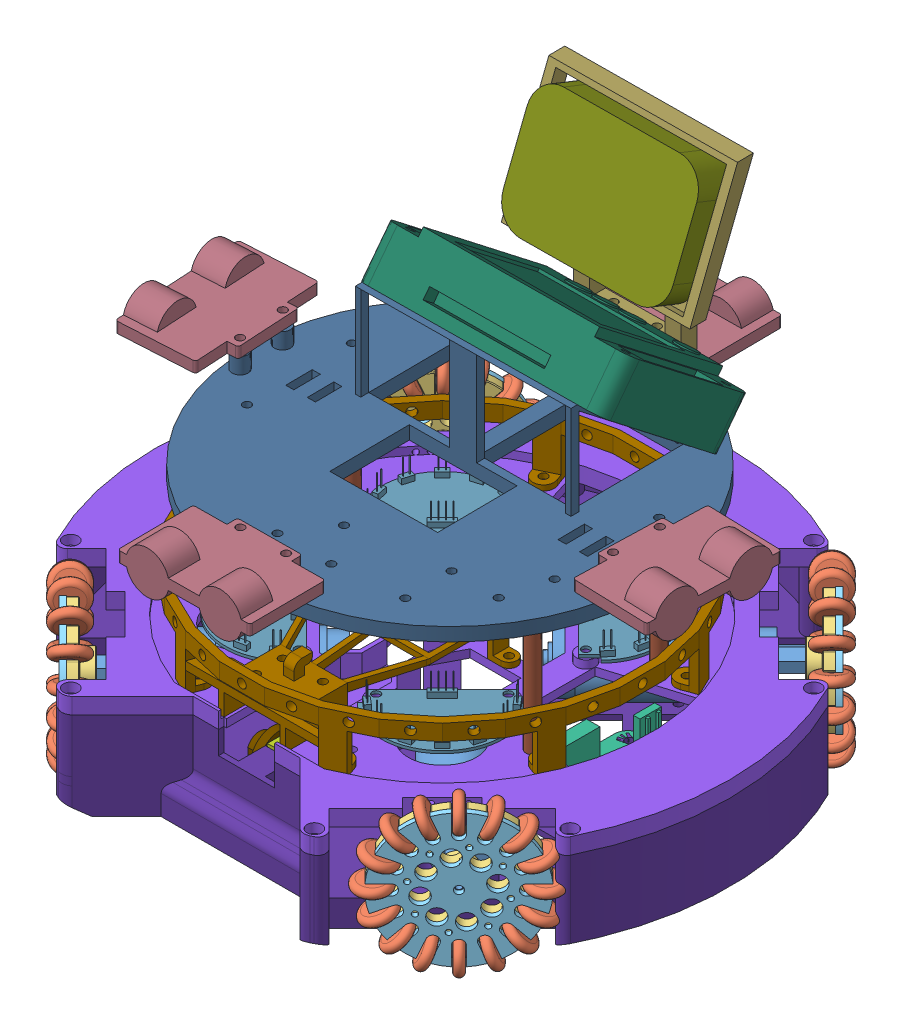
SolidWorks assembly 0623, configuration 默认. Lengths in mm.
Overall size (215 174.45 207.54).
171 component instances, 18 part files, 36 mates.
Components (placement in the parent):
- 马达25-1: 马达25 [預設] at (54.8373 -31.5326 209.9849) x (-0.000306 -1 -0.000306) z (-0.707107 0 0.707107) size (61.22 59.79 89.47)
  - 輕量空心杯電機BY亨哥-1: 輕量空心杯電機BY亨哥 [預設] at (4.2662 -2.1089 38.7) size (23 23 77.4)
  - 全向輪-1: 全向輪 [預設] at (-15.6348 -2.7534 102.1854) x (0.994045 0 -0.108967) z (0.108967 0 0.994045) size (59.43 59.79 19.63)
    - 小輪-3: 小輪 [預設] at (-13.3411 -5.1734 12.5) size (12.5 3.5 12.5)
    - 全向輪鋁-3: 全向輪鋁 [預設] at (18.6476 0.6445 12.5211) x (0.994045 0 0.108967) z (-0.108967 0 0.994045) size (49.74 49.74 8)
    - 軸-3: 軸 [預設] at (-4.4878 -6.2404 12.5) x (0 -1 0) z (-0.050863 0 0.998706) size (8.5 2 2)
    - 壓片-3: 壓片 [預設] at (18.2663 0.6445 16.0003) x (0.994045 0 0.108967) z (-0.108967 0 0.994045) size (49.84 49.84 2)
    - 軸-35: 軸 [預設] at (-0.1284 -14.518 12.9779) x (0.380405 -0.92388 0.0417) z (-0.055272 0.022297 0.998222) size (8.5 2 2)
    - 軸-36: 軸 [預設] at (7.048 -20.4873 13.7646) x (0.702896 -0.707107 0.077052) z (-0.067827 0.0412 0.996846) size (8.5 2 2)
    - 軸-37: 軸 [預設] at (15.9489 -23.2394 14.7403) x (0.918378 -0.382683 0.100673) z (-0.086618 0.053831 0.994786) size (8.5 2 2)
    - 軸-38: 軸 [預設] at (25.2192 -22.3555 15.7565) x (0.994045 0 0.108967) z (-0.108782 0.058266 0.992357) size (8.5 2 2)
    - 軸-39: 軸 [預設] at (33.4475 -17.9699 16.6585) x (0.918378 0.382683 0.100673) z (-0.130947 0.053831 0.989927) size (8.5 2 2)
    - 軸-40: 軸 [預設] at (39.3812 -10.7505 17.3089) x (0.702896 0.707107 0.077052) z (-0.149737 0.0412 0.987867) size (8.5 2 2)
    - 軸-41: 軸 [預設] at (42.117 -1.7963 17.6088) x (0.380405 0.92388 0.0417) z (-0.162293 0.022297 0.986491) size (8.5 2 2)
    - 軸-42: 軸 [預設] at (41.2383 7.5295 17.5125) x (0 1 0) z (-0.166701 0 0.986007) size (8.5 2 2)
    - 軸-43: 軸 [預設] at (36.8789 15.8071 17.0346) x (-0.380405 0.92388 -0.0417) z (-0.162293 -0.022297 0.986491) size (8.5 2 2)
    - 軸-44: 軸 [預設] at (29.7024 21.7764 16.2479) x (-0.702896 0.707107 -0.077052) z (-0.149737 -0.0412 0.987867) size (8.5 2 2)
    - 軸-45: 軸 [預設] at (20.8015 24.5285 15.2722) x (-0.918378 0.382683 -0.100673) z (-0.130947 -0.053831 0.989927) size (8.5 2 2)
    - 軸-46: 軸 [預設] at (11.5313 23.6445 14.256) x (-0.994045 0 -0.108967) z (-0.108782 -0.058266 0.992357) size (8.5 2 2)
    - 軸-47: 軸 [預設] at (3.3029 19.259 13.354) x (-0.918378 -0.382683 -0.100673) z (-0.086618 -0.053831 0.994786) size (8.5 2 2)
    - 軸-48: 軸 [預設] at (-2.6308 12.0396 12.7036) x (-0.702896 -0.707107 -0.077052) z (-0.067827 -0.0412 0.996846) size (8.5 2 2)
    - 軸-49: 軸 [預設] at (-5.3665 3.0854 12.4037) x (-0.380405 -0.92388 -0.0417) z (-0.055272 -0.022297 0.998222) size (8.5 2 2)
    - 小輪-4: 小輪 [預設] at (-8.7217 -16.9001 13.0064) x (0.924783 0.380405 -0.008245) z (-0.008245 0.0417 0.999096) size (12.5 3.5 12.5)
    - 小輪-5: 小輪 [預設] at (0.007 -25.9558 13.9632) x (0.710585 0.702896 -0.031726) z (-0.031726 0.077052 0.996522) size (12.5 3.5 12.5)
    - 小輪-6: 小輪 [預設] at (11.516 -30.9618 15.2248) x (0.390013 0.918378 -0.066867) z (-0.066867 0.100673 0.99267) size (12.5 3.5 12.5)
    - 小輪-7: 小輪 [預設] at (24.0533 -31.1561 16.5992) x (0.011874 0.994045 -0.108319) z (-0.108319 0.108967 0.988126) size (12.5 3.5 12.5)
    - 小輪-8: 小輪 [預設] at (35.7102 -26.509 17.877) x (-0.366266 0.918378 -0.14977) z (-0.14977 0.100673 0.983582) size (12.5 3.5 12.5)
    - 小輪-9: 小輪 [預設] at (44.712 -17.728 18.8638) x (-0.686837 0.702896 -0.184911) z (-0.184911 0.077052 0.97973) size (12.5 3.5 12.5)
    - 小輪-10: 小輪 [預設] at (49.6882 -6.15 19.4093) x (-0.901036 0.380405 -0.208392) z (-0.208392 0.0417 0.977156) size (12.5 3.5 12.5)
    - 小輪-11: 小輪 [預設] at (49.8813 6.4624 19.4305) x (-0.976252 0 -0.216637) z (-0.216637 0 0.976252) size (12.5 3.5 12.5)
    - 小輪-12: 小輪 [預設] at (45.2619 18.1891 18.9241) x (-0.901036 -0.380405 -0.208392) z (-0.208392 -0.0417 0.977156) size (12.5 3.5 12.5)
    - 小輪-13: 小輪 [預設] at (36.5332 27.2448 17.9672) x (-0.686837 -0.702896 -0.184911) z (-0.184911 -0.077052 0.97973) size (12.5 3.5 12.5)
    - 小輪-14: 小輪 [預設] at (25.0242 32.2509 16.7056) x (-0.366266 -0.918378 -0.14977) z (-0.14977 -0.100673 0.983582) size (12.5 3.5 12.5)
    - 小輪-15: 小輪 [預設] at (12.4869 32.4451 15.3313) x (0.011874 -0.994045 -0.108319) z (-0.108319 -0.108967 0.988126) size (12.5 3.5 12.5)
    - 小輪-16: 小輪 [預設] at (0.83 27.798 14.0534) x (0.390013 -0.918378 -0.066867) z (-0.066867 -0.100673 0.99267) size (12.5 3.5 12.5)
    - 小輪-17: 小輪 [預設] at (-8.1718 19.0171 13.0667) x (0.710585 -0.702896 -0.031726) z (-0.031726 -0.077052 0.996522) size (12.5 3.5 12.5)
    - 小輪-18: 小輪 [預設] at (-13.148 7.4391 12.5212) x (0.924783 -0.380405 -0.008245) z (-0.008245 -0.0417 0.999096) size (12.5 3.5 12.5)
- 马达25-2: 马达25 [預設] at (34.6299 -31.5326 204.019) x (-0.000306 -1 0.000306) z (0.707107 0 0.707107) size (61.22 59.79 89.47)
  - 輕量空心杯電機BY亨哥-1: 輕量空心杯電機BY亨哥 [預設] at (4.2662 -2.1089 38.7) size (23 23 77.4)
  - 全向輪-1: 全向輪 [預設] at (-15.6348 -2.7534 102.1854) x (0.994045 0 -0.108967) z (0.108967 0 0.994045) size (59.43 59.79 19.63)
    - 小輪-3: 小輪 [預設] at (-13.3411 -5.1734 12.5) size (12.5 3.5 12.5)
    - 全向輪鋁-3: 全向輪鋁 [預設] at (18.6476 0.6445 12.5211) x (0.994045 0 0.108967) z (-0.108967 0 0.994045) size (49.74 49.74 8)
    - 軸-3: 軸 [預設] at (-4.4878 -6.2404 12.5) x (0 -1 0) z (-0.050863 0 0.998706) size (8.5 2 2)
    - 壓片-3: 壓片 [預設] at (18.2663 0.6445 16.0003) x (0.994045 0 0.108967) z (-0.108967 0 0.994045) size (49.84 49.84 2)
    - 軸-35: 軸 [預設] at (-0.1284 -14.518 12.9779) x (0.380405 -0.92388 0.0417) z (-0.055272 0.022297 0.998222) size (8.5 2 2)
    - 軸-36: 軸 [預設] at (7.048 -20.4873 13.7646) x (0.702896 -0.707107 0.077052) z (-0.067827 0.0412 0.996846) size (8.5 2 2)
    - 軸-37: 軸 [預設] at (15.9489 -23.2394 14.7403) x (0.918378 -0.382683 0.100673) z (-0.086618 0.053831 0.994786) size (8.5 2 2)
    - 軸-38: 軸 [預設] at (25.2192 -22.3555 15.7565) x (0.994045 0 0.108967) z (-0.108782 0.058266 0.992357) size (8.5 2 2)
    - 軸-39: 軸 [預設] at (33.4475 -17.9699 16.6585) x (0.918378 0.382683 0.100673) z (-0.130947 0.053831 0.989927) size (8.5 2 2)
    - 軸-40: 軸 [預設] at (39.3812 -10.7505 17.3089) x (0.702896 0.707107 0.077052) z (-0.149737 0.0412 0.987867) size (8.5 2 2)
    - 軸-41: 軸 [預設] at (42.117 -1.7963 17.6088) x (0.380405 0.92388 0.0417) z (-0.162293 0.022297 0.986491) size (8.5 2 2)
    - 軸-42: 軸 [預設] at (41.2383 7.5295 17.5125) x (0 1 0) z (-0.166701 0 0.986007) size (8.5 2 2)
    - 軸-43: 軸 [預設] at (36.8789 15.8071 17.0346) x (-0.380405 0.92388 -0.0417) z (-0.162293 -0.022297 0.986491) size (8.5 2 2)
    - 軸-44: 軸 [預設] at (29.7024 21.7764 16.2479) x (-0.702896 0.707107 -0.077052) z (-0.149737 -0.0412 0.987867) size (8.5 2 2)
    - 軸-45: 軸 [預設] at (20.8015 24.5285 15.2722) x (-0.918378 0.382683 -0.100673) z (-0.130947 -0.053831 0.989927) size (8.5 2 2)
    - 軸-46: 軸 [預設] at (11.5313 23.6445 14.256) x (-0.994045 0 -0.108967) z (-0.108782 -0.058266 0.992357) size (8.5 2 2)
    - 軸-47: 軸 [預設] at (3.3029 19.259 13.354) x (-0.918378 -0.382683 -0.100673) z (-0.086618 -0.053831 0.994786) size (8.5 2 2)
    - 軸-48: 軸 [預設] at (-2.6308 12.0396 12.7036) x (-0.702896 -0.707107 -0.077052) z (-0.067827 -0.0412 0.996846) size (8.5 2 2)
    - 軸-49: 軸 [預設] at (-5.3665 3.0854 12.4037) x (-0.380405 -0.92388 -0.0417) z (-0.055272 -0.022297 0.998222) size (8.5 2 2)
    - 小輪-4: 小輪 [預設] at (-8.7217 -16.9001 13.0064) x (0.924783 0.380405 -0.008245) z (-0.008245 0.0417 0.999096) size (12.5 3.5 12.5)
    - 小輪-5: 小輪 [預設] at (0.007 -25.9558 13.9632) x (0.710585 0.702896 -0.031726) z (-0.031726 0.077052 0.996522) size (12.5 3.5 12.5)
    - 小輪-6: 小輪 [預設] at (11.516 -30.9618 15.2248) x (0.390013 0.918378 -0.066867) z (-0.066867 0.100673 0.99267) size (12.5 3.5 12.5)
    - 小輪-7: 小輪 [預設] at (24.0533 -31.1561 16.5992) x (0.011874 0.994045 -0.108319) z (-0.108319 0.108967 0.988126) size (12.5 3.5 12.5)
    - 小輪-8: 小輪 [預設] at (35.7102 -26.509 17.877) x (-0.366266 0.918378 -0.14977) z (-0.14977 0.100673 0.983582) size (12.5 3.5 12.5)
    - 小輪-9: 小輪 [預設] at (44.712 -17.728 18.8638) x (-0.686837 0.702896 -0.184911) z (-0.184911 0.077052 0.97973) size (12.5 3.5 12.5)
    - 小輪-10: 小輪 [預設] at (49.6882 -6.15 19.4093) x (-0.901036 0.380405 -0.208392) z (-0.208392 0.0417 0.977156) size (12.5 3.5 12.5)
    - 小輪-11: 小輪 [預設] at (49.8813 6.4624 19.4305) x (-0.976252 0 -0.216637) z (-0.216637 0 0.976252) size (12.5 3.5 12.5)
    - 小輪-12: 小輪 [預設] at (45.2619 18.1891 18.9241) x (-0.901036 -0.380405 -0.208392) z (-0.208392 -0.0417 0.977156) size (12.5 3.5 12.5)
    - 小輪-13: 小輪 [預設] at (36.5332 27.2448 17.9672) x (-0.686837 -0.702896 -0.184911) z (-0.184911 -0.077052 0.97973) size (12.5 3.5 12.5)
    - 小輪-14: 小輪 [預設] at (25.0242 32.2509 16.7056) x (-0.366266 -0.918378 -0.14977) z (-0.14977 -0.100673 0.983582) size (12.5 3.5 12.5)
    - 小輪-15: 小輪 [預設] at (12.4869 32.4451 15.3313) x (0.011874 -0.994045 -0.108319) z (-0.108319 -0.108967 0.988126) size (12.5 3.5 12.5)
    - 小輪-16: 小輪 [預設] at (0.83 27.798 14.0534) x (0.390013 -0.918378 -0.066867) z (-0.066867 -0.100673 0.99267) size (12.5 3.5 12.5)
    - 小輪-17: 小輪 [預設] at (-8.1718 19.0171 13.0667) x (0.710585 -0.702896 -0.031726) z (-0.031726 -0.077052 0.996522) size (12.5 3.5 12.5)
    - 小輪-18: 小輪 [預設] at (-13.148 7.4391 12.5212) x (0.924783 -0.380405 -0.008245) z (-0.008245 -0.0417 0.999096) size (12.5 3.5 12.5)
- 马达25-3: 马达25 [預設] at (28.664 -31.5326 224.2263) x (0.000306 -1 0.000306) z (0.707107 0 -0.707107) size (61.22 59.79 89.47)
  - 輕量空心杯電機BY亨哥-1: 輕量空心杯電機BY亨哥 [預設] at (4.2662 -2.1089 38.7) size (23 23 77.4)
  - 全向輪-1: 全向輪 [預設] at (-15.6348 -2.7534 102.1854) x (0.994045 0 -0.108967) z (0.108967 0 0.994045) size (59.43 59.79 19.63)
    - 小輪-3: 小輪 [預設] at (-13.3411 -5.1734 12.5) size (12.5 3.5 12.5)
    - 全向輪鋁-3: 全向輪鋁 [預設] at (18.6476 0.6445 12.5211) x (0.994045 0 0.108967) z (-0.108967 0 0.994045) size (49.74 49.74 8)
    - 軸-3: 軸 [預設] at (-4.4878 -6.2404 12.5) x (0 -1 0) z (-0.050863 0 0.998706) size (8.5 2 2)
    - 壓片-3: 壓片 [預設] at (18.2663 0.6445 16.0003) x (0.994045 0 0.108967) z (-0.108967 0 0.994045) size (49.84 49.84 2)
    - 軸-35: 軸 [預設] at (-0.1284 -14.518 12.9779) x (0.380405 -0.92388 0.0417) z (-0.055272 0.022297 0.998222) size (8.5 2 2)
    - 軸-36: 軸 [預設] at (7.048 -20.4873 13.7646) x (0.702896 -0.707107 0.077052) z (-0.067827 0.0412 0.996846) size (8.5 2 2)
    - 軸-37: 軸 [預設] at (15.9489 -23.2394 14.7403) x (0.918378 -0.382683 0.100673) z (-0.086618 0.053831 0.994786) size (8.5 2 2)
    - 軸-38: 軸 [預設] at (25.2192 -22.3555 15.7565) x (0.994045 0 0.108967) z (-0.108782 0.058266 0.992357) size (8.5 2 2)
    - 軸-39: 軸 [預設] at (33.4475 -17.9699 16.6585) x (0.918378 0.382683 0.100673) z (-0.130947 0.053831 0.989927) size (8.5 2 2)
    - 軸-40: 軸 [預設] at (39.3812 -10.7505 17.3089) x (0.702896 0.707107 0.077052) z (-0.149737 0.0412 0.987867) size (8.5 2 2)
    - 軸-41: 軸 [預設] at (42.117 -1.7963 17.6088) x (0.380405 0.92388 0.0417) z (-0.162293 0.022297 0.986491) size (8.5 2 2)
    - 軸-42: 軸 [預設] at (41.2383 7.5295 17.5125) x (0 1 0) z (-0.166701 0 0.986007) size (8.5 2 2)
    - 軸-43: 軸 [預設] at (36.8789 15.8071 17.0346) x (-0.380405 0.92388 -0.0417) z (-0.162293 -0.022297 0.986491) size (8.5 2 2)
    - 軸-44: 軸 [預設] at (29.7024 21.7764 16.2479) x (-0.702896 0.707107 -0.077052) z (-0.149737 -0.0412 0.987867) size (8.5 2 2)
    - 軸-45: 軸 [預設] at (20.8015 24.5285 15.2722) x (-0.918378 0.382683 -0.100673) z (-0.130947 -0.053831 0.989927) size (8.5 2 2)
    - 軸-46: 軸 [預設] at (11.5313 23.6445 14.256) x (-0.994045 0 -0.108967) z (-0.108782 -0.058266 0.992357) size (8.5 2 2)
    - 軸-47: 軸 [預設] at (3.3029 19.259 13.354) x (-0.918378 -0.382683 -0.100673) z (-0.086618 -0.053831 0.994786) size (8.5 2 2)
    - 軸-48: 軸 [預設] at (-2.6308 12.0396 12.7036) x (-0.702896 -0.707107 -0.077052) z (-0.067827 -0.0412 0.996846) size (8.5 2 2)
    - 軸-49: 軸 [預設] at (-5.3665 3.0854 12.4037) x (-0.380405 -0.92388 -0.0417) z (-0.055272 -0.022297 0.998222) size (8.5 2 2)
    - 小輪-4: 小輪 [預設] at (-8.7217 -16.9001 13.0064) x (0.924783 0.380405 -0.008245) z (-0.008245 0.0417 0.999096) size (12.5 3.5 12.5)
    - 小輪-5: 小輪 [預設] at (0.007 -25.9558 13.9632) x (0.710585 0.702896 -0.031726) z (-0.031726 0.077052 0.996522) size (12.5 3.5 12.5)
    - 小輪-6: 小輪 [預設] at (11.516 -30.9618 15.2248) x (0.390013 0.918378 -0.066867) z (-0.066867 0.100673 0.99267) size (12.5 3.5 12.5)
    - 小輪-7: 小輪 [預設] at (24.0533 -31.1561 16.5992) x (0.011874 0.994045 -0.108319) z (-0.108319 0.108967 0.988126) size (12.5 3.5 12.5)
    - 小輪-8: 小輪 [預設] at (35.7102 -26.509 17.877) x (-0.366266 0.918378 -0.14977) z (-0.14977 0.100673 0.983582) size (12.5 3.5 12.5)
    - 小輪-9: 小輪 [預設] at (44.712 -17.728 18.8638) x (-0.686837 0.702896 -0.184911) z (-0.184911 0.077052 0.97973) size (12.5 3.5 12.5)
    - 小輪-10: 小輪 [預設] at (49.6882 -6.15 19.4093) x (-0.901036 0.380405 -0.208392) z (-0.208392 0.0417 0.977156) size (12.5 3.5 12.5)
    - 小輪-11: 小輪 [預設] at (49.8813 6.4624 19.4305) x (-0.976252 0 -0.216637) z (-0.216637 0 0.976252) size (12.5 3.5 12.5)
    - 小輪-12: 小輪 [預設] at (45.2619 18.1891 18.9241) x (-0.901036 -0.380405 -0.208392) z (-0.208392 -0.0417 0.977156) size (12.5 3.5 12.5)
    - 小輪-13: 小輪 [預設] at (36.5332 27.2448 17.9672) x (-0.686837 -0.702896 -0.184911) z (-0.184911 -0.077052 0.97973) size (12.5 3.5 12.5)
    - 小輪-14: 小輪 [預設] at (25.0242 32.2509 16.7056) x (-0.366266 -0.918378 -0.14977) z (-0.14977 -0.100673 0.983582) size (12.5 3.5 12.5)
    - 小輪-15: 小輪 [預設] at (12.4869 32.4451 15.3313) x (0.011874 -0.994045 -0.108319) z (-0.108319 -0.108967 0.988126) size (12.5 3.5 12.5)
    - 小輪-16: 小輪 [預設] at (0.83 27.798 14.0534) x (0.390013 -0.918378 -0.066867) z (-0.066867 -0.100673 0.99267) size (12.5 3.5 12.5)
    - 小輪-17: 小輪 [預設] at (-8.1718 19.0171 13.0667) x (0.710585 -0.702896 -0.031726) z (-0.031726 -0.077052 0.996522) size (12.5 3.5 12.5)
    - 小輪-18: 小輪 [預設] at (-13.148 7.4391 12.5212) x (0.924783 -0.380405 -0.008245) z (-0.008245 -0.0417 0.999096) size (12.5 3.5 12.5)
- 马达25-4: 马达25 [預設] at (48.8714 -31.5326 230.1922) x (0.000306 -1 -0.000306) z (-0.707107 0 -0.707107) size (61.22 59.79 89.47)
  - 輕量空心杯電機BY亨哥-1: 輕量空心杯電機BY亨哥 [預設] at (4.2662 -2.1089 38.7) size (23 23 77.4)
  - 全向輪-1: 全向輪 [預設] at (-15.6348 -2.7534 102.1854) x (0.994045 0 -0.108967) z (0.108967 0 0.994045) size (59.43 59.79 19.63)
    - 小輪-3: 小輪 [預設] at (-13.3411 -5.1734 12.5) size (12.5 3.5 12.5)
    - 全向輪鋁-3: 全向輪鋁 [預設] at (18.6476 0.6445 12.5211) x (0.994045 0 0.108967) z (-0.108967 0 0.994045) size (49.74 49.74 8)
    - 軸-3: 軸 [預設] at (-4.4878 -6.2404 12.5) x (0 -1 0) z (-0.050863 0 0.998706) size (8.5 2 2)
    - 壓片-3: 壓片 [預設] at (18.2663 0.6445 16.0003) x (0.994045 0 0.108967) z (-0.108967 0 0.994045) size (49.84 49.84 2)
    - 軸-35: 軸 [預設] at (-0.1284 -14.518 12.9779) x (0.380405 -0.92388 0.0417) z (-0.055272 0.022297 0.998222) size (8.5 2 2)
    - 軸-36: 軸 [預設] at (7.048 -20.4873 13.7646) x (0.702896 -0.707107 0.077052) z (-0.067827 0.0412 0.996846) size (8.5 2 2)
    - 軸-37: 軸 [預設] at (15.9489 -23.2394 14.7403) x (0.918378 -0.382683 0.100673) z (-0.086618 0.053831 0.994786) size (8.5 2 2)
    - 軸-38: 軸 [預設] at (25.2192 -22.3555 15.7565) x (0.994045 0 0.108967) z (-0.108782 0.058266 0.992357) size (8.5 2 2)
    - 軸-39: 軸 [預設] at (33.4475 -17.9699 16.6585) x (0.918378 0.382683 0.100673) z (-0.130947 0.053831 0.989927) size (8.5 2 2)
    - 軸-40: 軸 [預設] at (39.3812 -10.7505 17.3089) x (0.702896 0.707107 0.077052) z (-0.149737 0.0412 0.987867) size (8.5 2 2)
    - 軸-41: 軸 [預設] at (42.117 -1.7963 17.6088) x (0.380405 0.92388 0.0417) z (-0.162293 0.022297 0.986491) size (8.5 2 2)
    - 軸-42: 軸 [預設] at (41.2383 7.5295 17.5125) x (0 1 0) z (-0.166701 0 0.986007) size (8.5 2 2)
    - 軸-43: 軸 [預設] at (36.8789 15.8071 17.0346) x (-0.380405 0.92388 -0.0417) z (-0.162293 -0.022297 0.986491) size (8.5 2 2)
    - 軸-44: 軸 [預設] at (29.7024 21.7764 16.2479) x (-0.702896 0.707107 -0.077052) z (-0.149737 -0.0412 0.987867) size (8.5 2 2)
    - 軸-45: 軸 [預設] at (20.8015 24.5285 15.2722) x (-0.918378 0.382683 -0.100673) z (-0.130947 -0.053831 0.989927) size (8.5 2 2)
    - 軸-46: 軸 [預設] at (11.5313 23.6445 14.256) x (-0.994045 0 -0.108967) z (-0.108782 -0.058266 0.992357) size (8.5 2 2)
    - 軸-47: 軸 [預設] at (3.3029 19.259 13.354) x (-0.918378 -0.382683 -0.100673) z (-0.086618 -0.053831 0.994786) size (8.5 2 2)
    - 軸-48: 軸 [預設] at (-2.6308 12.0396 12.7036) x (-0.702896 -0.707107 -0.077052) z (-0.067827 -0.0412 0.996846) size (8.5 2 2)
    - 軸-49: 軸 [預設] at (-5.3665 3.0854 12.4037) x (-0.380405 -0.92388 -0.0417) z (-0.055272 -0.022297 0.998222) size (8.5 2 2)
    - 小輪-4: 小輪 [預設] at (-8.7217 -16.9001 13.0064) x (0.924783 0.380405 -0.008245) z (-0.008245 0.0417 0.999096) size (12.5 3.5 12.5)
    - 小輪-5: 小輪 [預設] at (0.007 -25.9558 13.9632) x (0.710585 0.702896 -0.031726) z (-0.031726 0.077052 0.996522) size (12.5 3.5 12.5)
    - 小輪-6: 小輪 [預設] at (11.516 -30.9618 15.2248) x (0.390013 0.918378 -0.066867) z (-0.066867 0.100673 0.99267) size (12.5 3.5 12.5)
    - 小輪-7: 小輪 [預設] at (24.0533 -31.1561 16.5992) x (0.011874 0.994045 -0.108319) z (-0.108319 0.108967 0.988126) size (12.5 3.5 12.5)
    - 小輪-8: 小輪 [預設] at (35.7102 -26.509 17.877) x (-0.366266 0.918378 -0.14977) z (-0.14977 0.100673 0.983582) size (12.5 3.5 12.5)
    - 小輪-9: 小輪 [預設] at (44.712 -17.728 18.8638) x (-0.686837 0.702896 -0.184911) z (-0.184911 0.077052 0.97973) size (12.5 3.5 12.5)
    - 小輪-10: 小輪 [預設] at (49.6882 -6.15 19.4093) x (-0.901036 0.380405 -0.208392) z (-0.208392 0.0417 0.977156) size (12.5 3.5 12.5)
    - 小輪-11: 小輪 [預設] at (49.8813 6.4624 19.4305) x (-0.976252 0 -0.216637) z (-0.216637 0 0.976252) size (12.5 3.5 12.5)
    - 小輪-12: 小輪 [預設] at (45.2619 18.1891 18.9241) x (-0.901036 -0.380405 -0.208392) z (-0.208392 -0.0417 0.977156) size (12.5 3.5 12.5)
    - 小輪-13: 小輪 [預設] at (36.5332 27.2448 17.9672) x (-0.686837 -0.702896 -0.184911) z (-0.184911 -0.077052 0.97973) size (12.5 3.5 12.5)
    - 小輪-14: 小輪 [預設] at (25.0242 32.2509 16.7056) x (-0.366266 -0.918378 -0.14977) z (-0.14977 -0.100673 0.983582) size (12.5 3.5 12.5)
    - 小輪-15: 小輪 [預設] at (12.4869 32.4451 15.3313) x (0.011874 -0.994045 -0.108319) z (-0.108319 -0.108967 0.988126) size (12.5 3.5 12.5)
    - 小輪-16: 小輪 [預設] at (0.83 27.798 14.0534) x (0.390013 -0.918378 -0.066867) z (-0.066867 -0.100673 0.99267) size (12.5 3.5 12.5)
    - 小輪-17: 小輪 [預設] at (-8.1718 19.0171 13.0667) x (0.710585 -0.702896 -0.031726) z (-0.031726 -0.077052 0.996522) size (12.5 3.5 12.5)
    - 小輪-18: 小輪 [預設] at (-13.148 7.4391 12.5212) x (0.924783 -0.380405 -0.008245) z (-0.008245 -0.0417 0.999096) size (12.5 3.5 12.5)
- 四路驅動BY蘇-1: 四路驅動BY蘇 [預設] at (116.1068 -43.7979 220.2304) x (1 0 0) z (0 1 0) size (55 45 19)
- kick-motor-1: kick-motor [Default] at (42.2555 -47.3169 262.5875) x (0 0 -1) z (0.998373 0.057016 0) size (48 16 26)
- V12中-1: V12中 [Default] at (41.6068 -18.2979 220.2304) x (-1 0 0) z (0 0 1) size (215 29 204.53)
- V12眼-1: V12眼 [Default] at (41.6068 -0.2979 220.2304) x (-1 0 0) z (0 0 1) size (150 21 150)
- 123123-1: 123123 [Default] at (41.0487 23.7021 216.8053) x (-0.999961 0 0.008887) z (-0.008887 0 -0.999961) size (150 40 150)
- 轴45-1: 轴45 [默认] at (99.3493 -21.2979 244.1481) x (0.896107 0 0.443837) z (0 1 0) size (5 5 45)
- 轴45-2: 轴45 [默认] at (97.8598 -21.2979 195.2995) x (0.847705 0 0.530469) z (0 1 0) size (5 5 45)
- 轴45-3: 轴45 [默认] at (-16.1356 -21.2979 196.3127) x (0.43894 0 0.898516) z (0 1 0) size (5 5 45)
- 轴45-4: 轴45 [默认] at (-16.1356 -21.2979 244.1481) x (0.356553 0 0.934275) z (0 1 0) size (5 5 45)
- cam-old-1: cam-old [Default] at (40.4266 38.7021 146.808) x (-0.999961 0 0.008887) z (-0.008887 0 -0.999961) size (70 68 24.01)
- 中鳴超声BY亨哥-1: 中鳴超声BY亨哥 [預設] at (40.8044 34.7021 133.0541) x (0.999961 0 -0.008887) z (0 1 0) size (49 32.5 16)
- 中鳴超声BY亨哥-3: 中鳴超声BY亨哥 [預設] at (41.2931 34.7021 300.5564) x (-0.999961 0 0.008887) z (0 1 0) size (49 32.5 16)
- eye-2: eye [Default] at (78.3764 -18.2979 256.9999) x (-0.707107 0 0.707107) z (-0.707107 0 -0.707107) size (45 9 28)
- eye-3: eye [Default] at (78.3764 -18.2979 183.4608) x (0.707107 0 0.707107) z (-0.707107 0 0.707107) size (45 9 28)
- eye-5: eye [Default] at (4.8373 -18.2979 183.4608) x (0.707107 0 -0.707107) z (0.707107 0 0.707107) size (45 9 28)
- eye-8: eye [Default] at (4.8373 -18.2979 256.9999) x (-0.707107 0 -0.707107) z (0.707107 0 -0.707107) size (45 9 28)
- 中鳴超声BY亨哥-5: 中鳴超声BY亨哥 [預設] at (124.4613 34.7021 217.0957) x (-0.030262 0 0.999542) z (0 1 0) size (49 32.5 16)
- 中鳴超声BY亨哥-8: 中鳴超声BY亨哥 [預設] at (-43.093 34.7021 217.7311) x (-0.057453 0 -0.998348) z (0 1 0) size (49 32.5 16)
- X3RCU-1: X3RCU [默认] at (45.795 47.7397 188.2388) x (-0.999961 0 0.008887) z (-0.007015 -0.613941 -0.789321) size (91 21.5 59)
- cam-2: cam [默认] at (40.6558 82.9023 150.095) x (0.999961 0 -0.008887) z (0.008252 0.371391 0.92844) size (63 44 36)
- V10底-2: V10底 [Default] at (41.6068 -57.2979 220.2304) size (215 33 204.54)
- V10-kick1-2: V10-kick1 [GB - Spur gear 1M 20T 20PA 3FW ---S20A75H50L3.0N] at (33.8124 -39.7861 275.5875) x (0.998373 0.057016 0) z (0.000679 -0.011886 -0.999929) size (8 19.83 19.65)
- V10-kick1-3: V10-kick1 [GB - Spur gear 1M 20T 20PA 3FW ---S20A75H50L3.0N] at (49.7864 -38.8738 275.5875) x (-0.998373 -0.057016 0) z (-0.00282 0.049384 -0.998776) size (8 19.83 19.65)
Mates (geometry in assembly coordinates):
- 重合10: coincident aligned: circle of V12中-1; circle of V12眼-1
- 同心2: concentric anti-aligned: cylinder of V12中-1 through (-23.0647 -35.7979 193.4425) axis (0 1 0) radius 1.5; cylinder of V12眼-1 through (-23.0647 -19.2979 193.4425) axis (0 -1 0) radius 1.5
- 重合11: coincident: circle of V12中-1; circle of 轴45-2
- 重合12: coincident aligned: circle of V12中-1; circle of 轴45-1
- 重合13: coincident aligned: circle of V12中-1; circle of 轴45-4
- 重合14: coincident: circle of V12中-1; circle of 轴45-3
- 重合19: coincident: circle of 123123-1; circle of 轴45-3
- 同心4: concentric: circle of 123123-1; circle of 轴45-2
- 重合21: coincident anti-aligned: plane of 123123-1 through (32.4269 34.7021 146.8791) normal (0 1 0); plane of 中鳴超声BY亨哥-1 through (40.8044 34.7021 133.0541) normal (0 -1 0)
- 同心7: concentric anti-aligned: cylinder of 123123-1 through (32.4269 28.7021 146.8791) axis (0 -1 0) radius 1.5; cylinder of 中鳴超声BY亨哥-1 through (32.4269 26.7021 146.8791) axis (0 1 0) radius 1.5
- 平行5: parallel aligned: plane of 123123-1 through (61.0035 28.7021 211.6277) normal (0.008887 0 0.999961); plane of 中鳴超声BY亨哥-1 through (16.4498 38.7021 149.5212) normal (0.008887 0 0.999961)
- 同心8: concentric aligned: cylinder of 123123-1 through (48.4263 28.7021 146.7369) axis (0 -1 0) radius 1.5; cylinder of cam-old-1 through (48.4263 41.7021 146.7369) axis (0 -1 0) radius 1.5
- 重合23: coincident anti-aligned: plane of cam-old-1 through (40.4266 38.7021 146.808) normal (0 -1 0); plane of 中鳴超声BY亨哥-1 through (40.8044 38.7021 133.0541) normal (0 1 0)
- 同心9: concentric anti-aligned: cylinder of cam-old-1 through (32.4269 41.7021 146.8791) axis (0 -1 0) radius 1.5; cylinder of 中鳴超声BY亨哥-1 through (32.4269 26.7021 146.8791) axis (0 1 0) radius 1.5
- 重合26: coincident aligned: circle of 123123-1; circle of 中鳴超声BY亨哥-3
- 重合27: coincident aligned: circle of 123123-1; cylinder of 中鳴超声BY亨哥-3 through (49.6705 26.7021 286.7314) axis (0 1 0) radius 1.5
- 重合35: coincident aligned: circle of V12中-1; circle of eye-2
- 重合36: coincident aligned: circle of V12中-1; circle of eye-2
- 重合37: coincident aligned: circle of V12中-1; circle of eye-3
- 重合38: coincident aligned: circle of V12中-1; circle of eye-3
- 重合39: coincident aligned: circle of V12中-1; circle of eye-5
- 重合40: coincident aligned: circle of V12中-1; circle of eye-5
- 重合42: coincident aligned: circle of V12中-1; circle of eye-8
- 重合47: coincident aligned: circle of V12中-1; circle of eye-8
- 重合48: coincident aligned: circle of 123123-1; circle of 中鳴超声BY亨哥-5
- 重合52: coincident aligned: circle of 123123-1; circle of 中鳴超声BY亨哥-8
- 重合53: coincident anti-aligned: circle of 123123-1; circle of X3RCU-1
- 平行7: parallel anti-aligned: line of 123123-1 through (80.9761 63.7021 208.4501) axis (-0.999961 0 0.008887); line of X3RCU-1 through (5.5036 65.8509 211.8837) axis (0.999961 0 -0.008887)
- 重合55: coincident aligned: line of cam-old-1 through (8.8297 62.4758 158.5487) axis (0.999961 0 -0.008887); line of cam-2 through (19.2293 62.4758 158.4563) axis (0.999961 0 -0.008887)
- 重合56: coincident aligned: line of cam-old-1 through (72.2272 62.4758 157.9853) axis (-0.003301 0.928477 -0.371376); line of cam-2 through (72.1942 71.7605 154.2715) axis (-0.003301 0.928477 -0.371376)
- 重合58: coincident anti-aligned: plane of kick-motor-1 through (36.4096 -32.6477 280.5875) normal (-0.998373 -0.057016 0); plane of V10-kick1-2 through (36.8075 -39.615 275.5875) normal (0.998373 0.057016 0)
- 同心11: concentric aligned: cylinder of kick-motor-1 through (28.8206 -40.0711 275.5875) axis (0.998373 0.057016 0) radius 1.5; cylinder of V10-kick1-2 through (28.8206 -40.0711 275.5875) axis (0.998373 0.057016 0) radius 1.7
- 重合61: coincident anti-aligned: plane of kick-motor-1 through (46.3934 -32.0775 280.5875) normal (0.998373 0.057016 0); plane of V10-kick1-3 through (46.7913 -39.0449 275.5875) normal (-0.998373 -0.057016 0)
- 同心13: concentric aligned: cylinder of kick-motor-1 through (54.7783 -38.5887 275.5875) axis (-0.998373 -0.057016 0) radius 1.5; cylinder of V10-kick1-3 through (54.7783 -38.5887 275.5875) axis (-0.998373 -0.057016 0) radius 1.7
- 平行11: parallel aligned: line of kick-motor-1 through (48.1602 -45.4773 262.5875) axis (0 0 -1); line of V12中-1 through (49.1068 -47.2979 264.4699) axis (0 0 -1)
- 重合67: coincident anti-aligned: circle of V12中-1; circle of V10底-2
